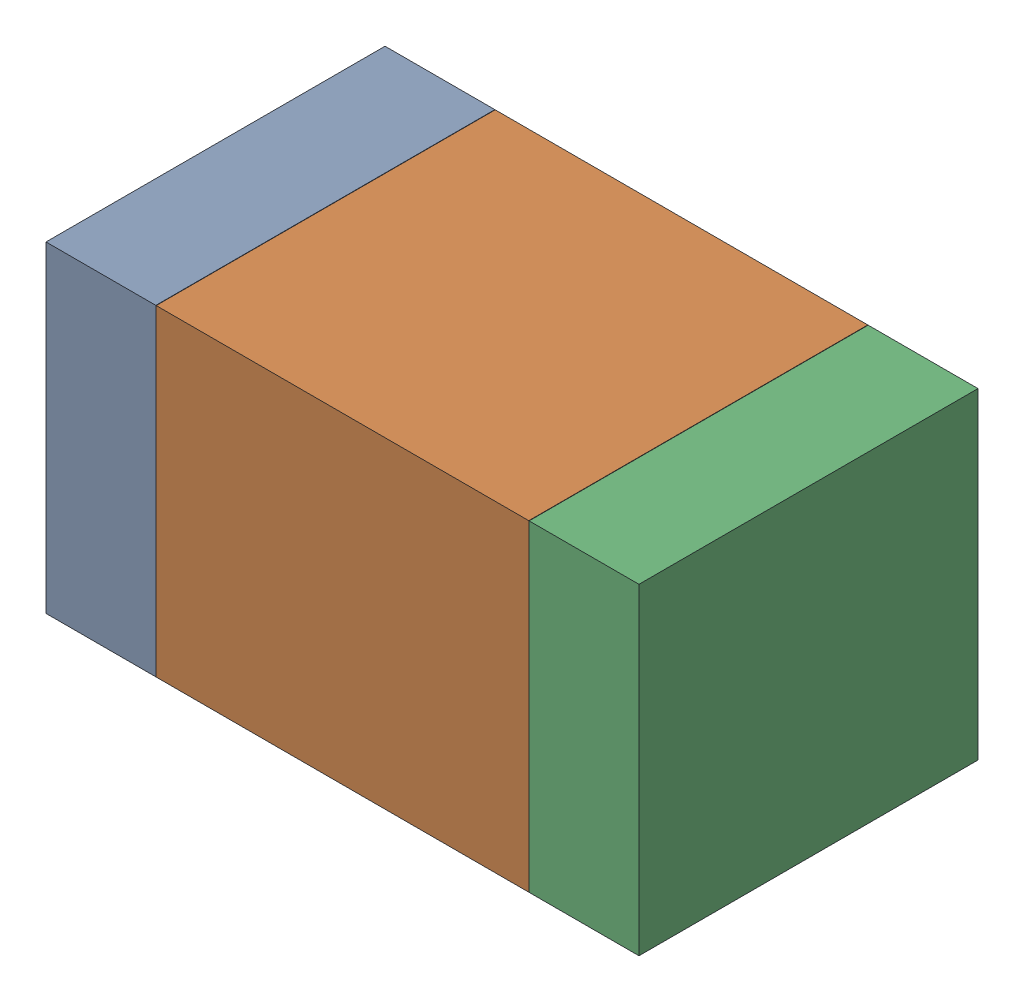
SolidWorks assembly R37, configuration Default. Lengths in mm.
Overall size (1.75 0.95 1).
6 component instances, 2 part files, 0 mates.
Components (placement in the parent):
- 6575498272-1: 6575498272 [Default] at (43.3565 21.971 0) size (0.32 0.95 1)
  - Extruded_8-1: Extruded_8 [Default] at origin size (0.32 0.95 1)
- 6575498112-1: 6575498112 [Default] at (44.069 21.971 0) size (1.1 0.95 1)
  - Extruded_9-1: Extruded_9 [Default] at origin size (1.1 0.95 1)
- 6575498272-2: 6575498272 [Default] at (44.7815 21.971 0) size (0.32 0.95 1)
  - Extruded_8-1: Extruded_8 [Default] at origin size (0.32 0.95 1)
